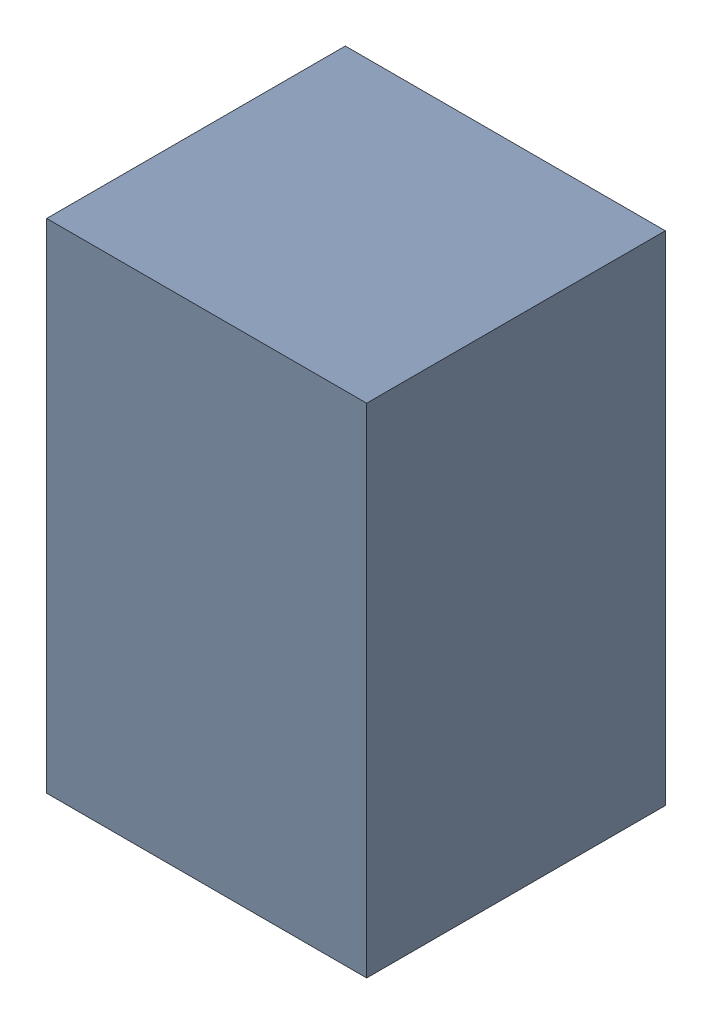
SolidWorks assembly C7_1, configuration Default. Lengths in mm.
Overall size (1.35 2.1 1.26).
2 component instances, 1 part files, 0 mates.
Components (placement in the parent):
- 407985696_1-1: 407985696_1 [Default] at (21.463 12.623 0.0127) size (1.35 2.1 1.26)
  - Extruded_6-1: Extruded_6 [Default] at origin size (1.35 2.1 1.26)
